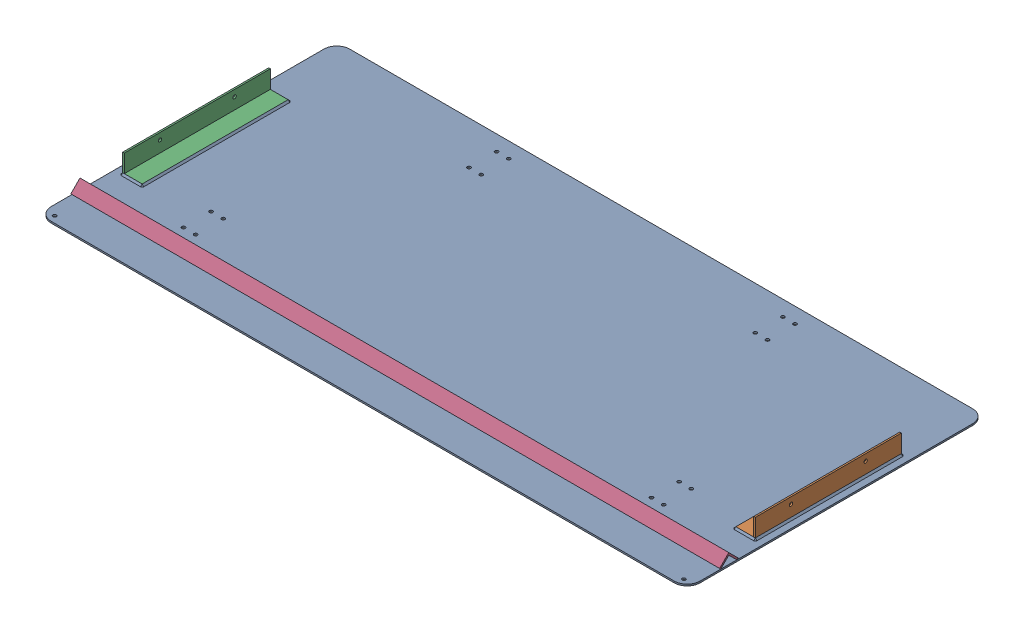
SolidWorks assembly GE-16159_ASM, configuration Default. Lengths in mm.
Overall size (1270 53.82 584.2).
5 component instances, 4 part files, 0 mates.
Components (placement in the parent):
- GE-16159_ASM-1: GE-16159_ASM [Default] at origin size (1244.6 3.17 292.1)
- GE-16016-1: GE-16016 [Default] at origin size (1270 3.17 584.2)
- GE-16159-01-1: GE-16159-01 [Default] at (619.125 3.175 0) x (0 0 1) z (-1 0 0) size (285.75 38.1 38.1)
- GE-16159-01-2: GE-16159-01 [Default] at (-619.125 3.175 0) x (0 0 -1) z (1 0 0) size (285.75 38.1 38.1)
- GE-16159-02-1: GE-16159-02 [Default] at (0 23.3806 210.6395) x (1 0 0) z (0 0.707107 -0.707107) size (1270 25.4 25.4)
